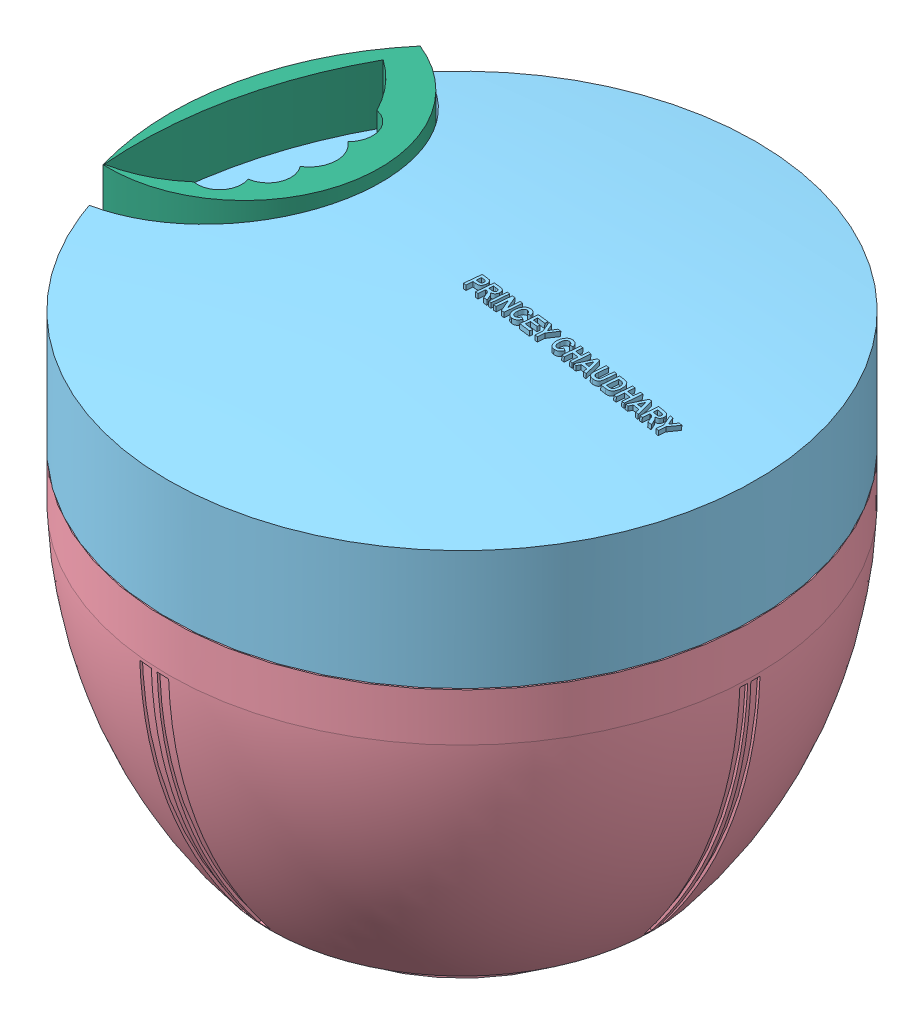
SolidWorks assembly ASSEMBLY_VEGETABLE CHOPPER_190030032, configuration Default. Lengths in mm.
Overall size (132.86 103.44 132.86).
10 component instances, 6 part files, 17 mates.
Components (placement in the parent):
- Part05_SHAFT_190030032-2: Part05_SHAFT_190030032 [Default] at (25.4073 -27.8102 -14.1058) x (0.999811 0 0.019419) z (-0.019419 0 0.999811) size (30 82 22.5)
- Part07_SCREW_FOR BLADES_190030032-2: Part07_SCREW_FOR BLADES_190030032 [Default] at (13.3554 -8.205 -14.3399) x (0.835155 0 -0.550015) z (0.550015 0 0.835155) size (1.9 3.95 1.9)
- Part03_BLADES_190030032-4: Part03_BLADES_190030032 [Default] at (3.8249 -7.8102 -1.113) x (-0.957591 0 0.288133) z (-0.288133 0 -0.957591) size (30.89 1 11.97)
- Part03_BLADES_190030032-5: Part03_BLADES_190030032 [Default] at (13.4801 7.1898 -34.552) x (-0.182321 0 -0.983239) z (0.983239 0 -0.182321) size (30.89 1 11.97)
- Part07_SCREW_FOR BLADES_190030032-3: Part07_SCREW_FOR BLADES_190030032 [Default] at (25.5925 6.795 -23.64) x (0.999997 0 -0.002278) z (0.002278 0 0.999997) size (1.9 3.95 1.9)
- Part03_BLADES_190030032-6: Part03_BLADES_190030032 [Default] at (46.7723 -23.8102 -25.8643) x (0.985698 0 -0.168524) z (0.168524 0 0.985698) size (30.89 1 11.97)
- Part07_SCREW_FOR BLADES_190030032-4: Part07_SCREW_FOR BLADES_190030032 [Default] at (35.6916 -24.205 -13.906) x (0.99961 0 -0.027941) z (0.027941 0 0.99961) size (1.9 3.95 1.9)
- Part01 CONTAINER_190030032-1: Part01 CONTAINER_190030032 [Default] at (25.4073 -27.8102 -14.1058) size (122.8 73 123.1)
- Part02_LID_190030032-1: Part02_LID_190030032 [Default] at (25.4073 32.4166 -14.1058) x (0.996329 0 0.085603) z (-0.085603 0 0.996329) size (122.8 40.21 122.8)
- Part06_HANDLE OR ROPE MECHANISM_190030032-1: Part06_HANDLE OR ROPE MECHANISM_190030032 [Default] at (-22.1463 59.9166 -52.9046) x (-0.208677 0 0.977985) z (-0.977985 0 -0.208677) size (55.87 12.3 30.66)
Mates (geometry in assembly coordinates):
- Coincident7: coincident anti-aligned: plane of Part05_SHAFT_190030032-2 through (25.4073 -6.8102 -14.1058) normal (0 -1 0); plane of Part03_BLADES_190030032-4 through (14.6845 -6.8102 4.0476) normal (0 1 0)
- Concentric6: concentric anti-aligned: cylinder of Part05_SHAFT_190030032-2 through (25.5925 10.1898 -23.64) axis (0 -1 0) radius 0.75; cylinder of Part07_SCREW_FOR BLADES_190030032-3 through (25.5925 10.7424 -23.64) axis (0 1 0) radius 0.75
- Coincident8: coincident aligned: plane of Part05_SHAFT_190030032-2 through (25.4073 9.1898 -14.1058) normal (0 1 0); circle of Part07_SCREW_FOR BLADES_190030032-3
- Lock1: lock: unknown of Part03_BLADES_190030032-5; unknown of Part07_SCREW_FOR BLADES_190030032-3
- Coincident9: coincident anti-aligned: plane of Part05_SHAFT_190030032-2 through (25.4073 8.1898 -14.1058) normal (0 -1 0); plane of Part03_BLADES_190030032-5 through (7.1696 8.1898 -24.3177) normal (0 1 0)
- Lock2: lock: unknown of Part05_SHAFT_190030032-2; unknown of Part07_SCREW_FOR BLADES_190030032-4
- Coincident10: coincident aligned: plane of Part05_SHAFT_190030032-2 through (25.4073 -21.8102 -14.1058) normal (0 1 0); circle of Part07_SCREW_FOR BLADES_190030032-4
- Concentric9: concentric aligned: cylinder of Part03_BLADES_190030032-6 through (35.6916 -32.8102 -13.906) axis (0 1 0) radius 0.75; cylinder of Part07_SCREW_FOR BLADES_190030032-4 through (35.6916 -20.2576 -13.906) axis (0 1 0) radius 0.75
- Coincident12: coincident: line of Part05_SHAFT_190030032-2 through (40.5113 -22.8102 -19.3135) axis (-0.019419 0 0.999811); plane of Part03_BLADES_190030032-6 through (36.6275 -22.8102 -32.3177) normal (0 1 0)
- Lock3: lock: unknown of Part05_SHAFT_190030032-2; unknown of Part07_SCREW_FOR BLADES_190030032-2
- Coincident13: coincident aligned: plane of Part05_SHAFT_190030032-2 through (25.4073 -5.8102 -14.1058) normal (0 1 0); circle of Part07_SCREW_FOR BLADES_190030032-2
- Concentric13: concentric aligned: cylinder of Part07_SCREW_FOR BLADES_190030032-2 through (13.3554 -4.2576 -14.3399) axis (0 1 0) radius 0.75; circle of Part03_BLADES_190030032-4
- Concentric11: concentric aligned: cylinder of Part05_SHAFT_190030032-2 through (25.4073 -16.8102 -14.1058) axis (0 -1 0) radius 2.1; circle of Part01 CONTAINER_190030032-1
- Coincident16: coincident aligned: plane of Part05_SHAFT_190030032-2 through (25.4073 -25.8102 -14.1058) normal (0 -1 0); circle of Part01 CONTAINER_190030032-1
- Concentric16: concentric aligned: circle of Part01 CONTAINER_190030032-1; circle of Part02_LID_190030032-1
- Coincident22: coincident aligned: plane of Part02_LID_190030032-1 through (-4.4821 59.9166 -19.6427) normal (0 1 0); circle of Part06_HANDLE OR ROPE MECHANISM_190030032-1
- Lock5: lock: unknown of Part01 CONTAINER_190030032-1; unknown of Part02_LID_190030032-1
